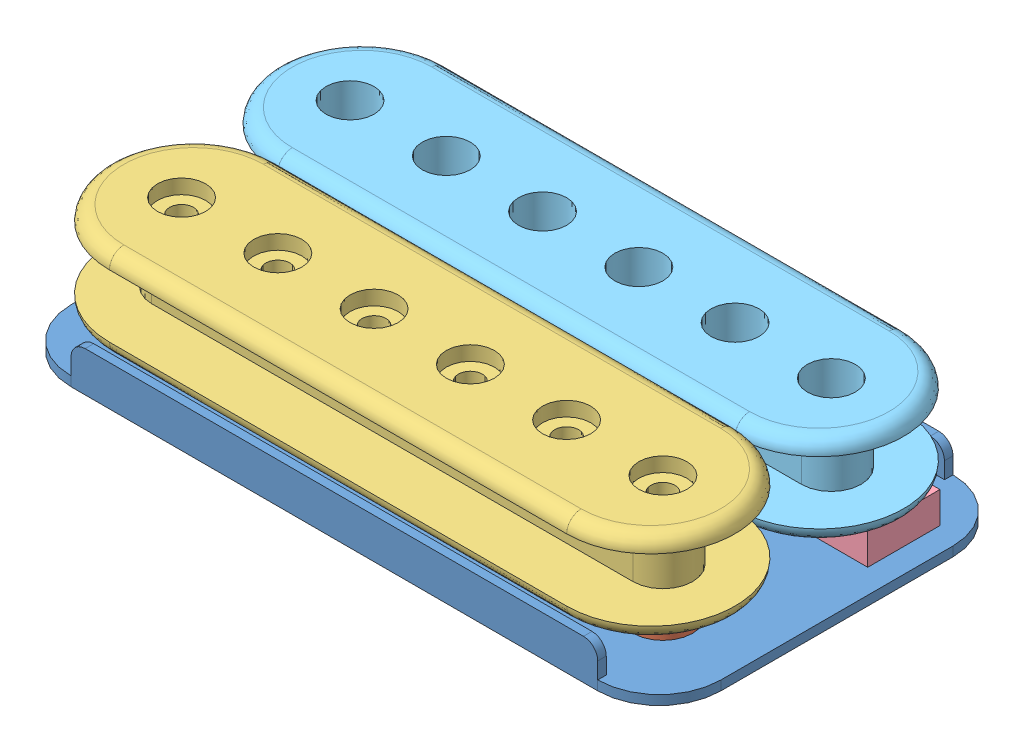
SolidWorks assembly Assem1, configuration Default. Lengths in mm.
Overall size (68.6 13.85 37.5).
5 component instances, 5 part files, 12 mates.
Components (placement in the parent):
- mounting plate-1: mounting plate [Default] at (17.2404 24.7521 63.136) size (68.6 4.24 37.5)
- spacer - screws-1: spacer - screws [Default] at (17.2404 25.7521 72.6106) size (57.1 3.2 6.3)
- bobbin screws-1: bobbin screws [Default] at (17.2404 28.9521 72.6106) size (66.04 9.65 17.78)
- spacer - magnet v2-1: spacer - magnet v2 [Default] at (17.2404 25.7521 53.5306) size (63.5 3.3 7.62)
- bobbin - magnet-1: bobbin - magnet [Default] at (17.2404 28.9521 54.8306) size (66.04 9.65 17.78)
Mates (geometry in assembly coordinates):
- Coincident1: coincident: plane of mounting plate-1 through (-10.5596 25.7521 50.886) normal (0 1 0); plane of spacer - screws-1 through (41.3704 25.7521 72.6106) normal (0 -1 0)
- Concentric1: concentric: circle of mounting plate-1; circle of spacer - screws-1
- Concentric2: concentric: circle of mounting plate-1; circle of spacer - screws-1
- Coincident2: coincident: plane of spacer - screws-1 through (17.2404 28.9521 72.6106) normal (0 1 0); plane of bobbin screws-1 through (41.3704 28.9521 72.6106) normal (0 -1 0)
- Coincident3: coincident: circle of spacer - screws-1; circle of bobbin screws-1
- Coincident4: coincident: circle of spacer - screws-1; circle of bobbin screws-1
- Coincident5: coincident: plane of mounting plate-1 through (-10.5596 25.7521 50.886) normal (0 1 0); plane of spacer - magnet v2-1 through (18.5383 25.7521 46.7105) normal (0 -1 0)
- Coincident6: coincident: plane of bobbin screws-1 through (41.3704 28.9521 72.6106) normal (0 -1 0); plane of bobbin - magnet-1 through (41.3704 28.9521 54.8306) normal (0 -1 0)
- Coincident7: coincident: plane of mounting plate-1 through (17.2404 24.7521 63.136) normal (1 0 0); plane of bobbin - magnet-1 through (17.2404 28.9521 54.8306) normal (1 0 0)
- Coincident8: coincident: line of bobbin screws-1 through (41.3704 37.0801 63.7206) axis (-1 0 0); line of bobbin - magnet-1 through (-6.8896 37.0801 63.7206) axis (1 0 0)
- Concentric3: concentric: circle of spacer - magnet v2-1; circle of bobbin - magnet-1
- Concentric4: concentric: circle of spacer - magnet v2-1; circle of bobbin - magnet-1
